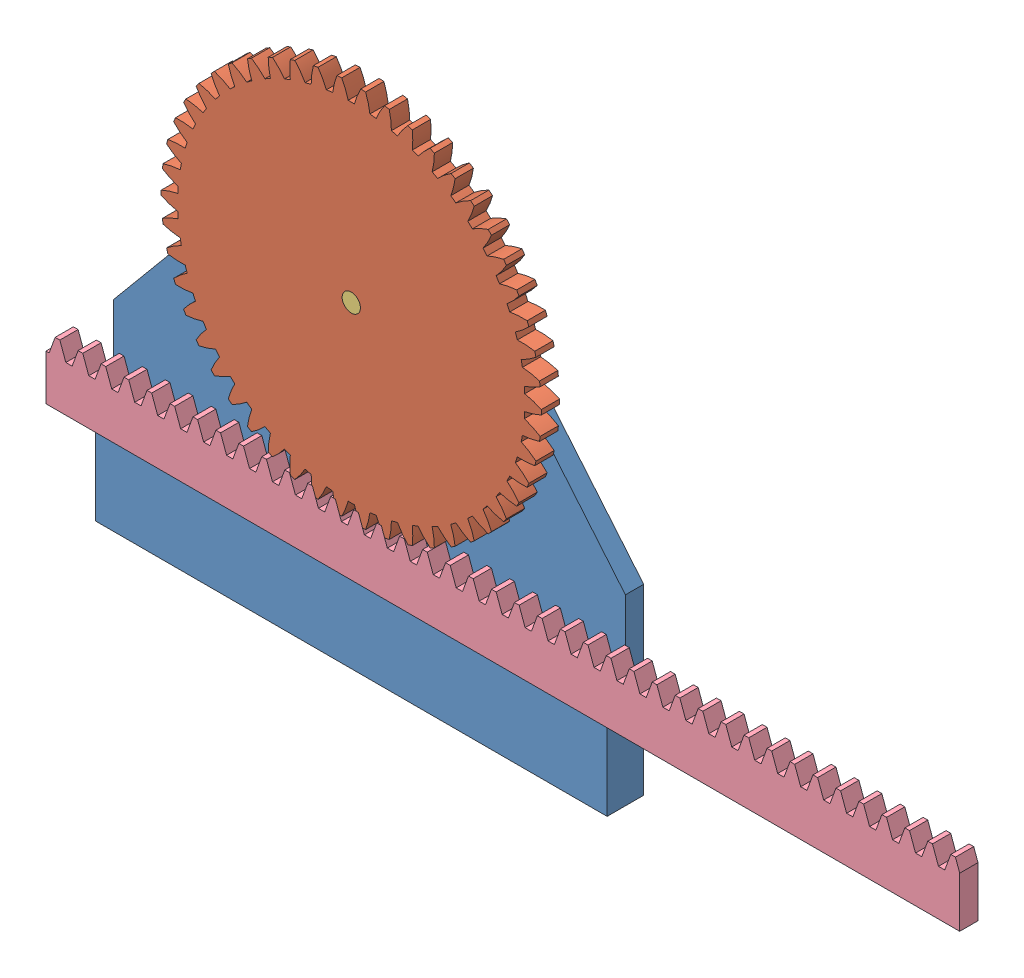
SolidWorks assembly Assem3, configuration Default. Lengths in mm.
Overall size (250 138.69 10).
4 component instances, 4 part files, 10 mates.
Components (placement in the parent):
- rp_base-1: rp_base [Default] at (9.5647 59.3966 10) size (140 110 10)
- rp_gear-1: rp_gear [Metric - Spur gear 2M 50T 20PA 5FW ---S50N75H50L5N] at (-70 86.7545 10) x (0 0 -1) z (1 0 0) size (5 103.87 104)
- rp_pin-1: rp_pin [Default] at (9.5647 59.3966 10) size (20 16.61 10)
- rp_rack-1: rp_rack [Metric - Rack-spur - rectangular 2M 20PA 5FW 15PH 250L---SAll] at (-153.5279 21.0008 10) size (250 17 5)
Mates (geometry in assembly coordinates):
- Coincident1: coincident anti-aligned: plane of rp_base-1 through (9.5647 0 0) normal (0 -1 0)
- Coincident2: coincident aligned: plane of rp_base-1 through (0 59.3966 5) normal (1 0 0)
- Coincident3: coincident: point of rp_base-1
- Coincident4: coincident anti-aligned: plane of rp_base-1 through (9.5647 21.0008 0) normal (0 1 0); plane of rp_rack-1 through (-153.5279 21.0008 5) normal (0 -1 0)
- Coincident5: coincident anti-aligned: plane of rp_base-1 through (9.5647 59.3966 5) normal (0 0 1); plane of rp_rack-1 through (-153.5279 38.0008 5) normal (0 0 -1)
- Coincident6: coincident anti-aligned: plane of rp_base-1 through (9.5647 59.3966 5) normal (0 0 1); plane of rp_gear-1 through (-70 86.7545 5) normal (0 0 -1)
- Concentric1: concentric anti-aligned: cylinder of rp_base-1 through (-70 86.7545 5) axis (0 0 -1) radius 10; cylinder of rp_pin-1 through (-70 86.7545 0) axis (0 0 1) radius 10
- Coincident7: coincident aligned: plane of rp_base-1 through (9.5647 59.3966 0) normal (0 0 -1); plane of rp_pin-1 through (9.5647 59.3966 0) normal (0 0 -1)
- Concentric2: concentric aligned: cylinder of rp_gear-1 through (-70 86.7545 -40.0001) axis (0 0 1) radius 2.5; cylinder of rp_pin-1 through (-70 86.7545 0) axis (0 0 1) radius 2.5
- Coincident8: coincident aligned: plane of rp_gear-1 through (-70 86.7545 10) normal (0 0 1); plane of rp_pin-1 through (9.5647 59.3966 10) normal (0 0 1)
